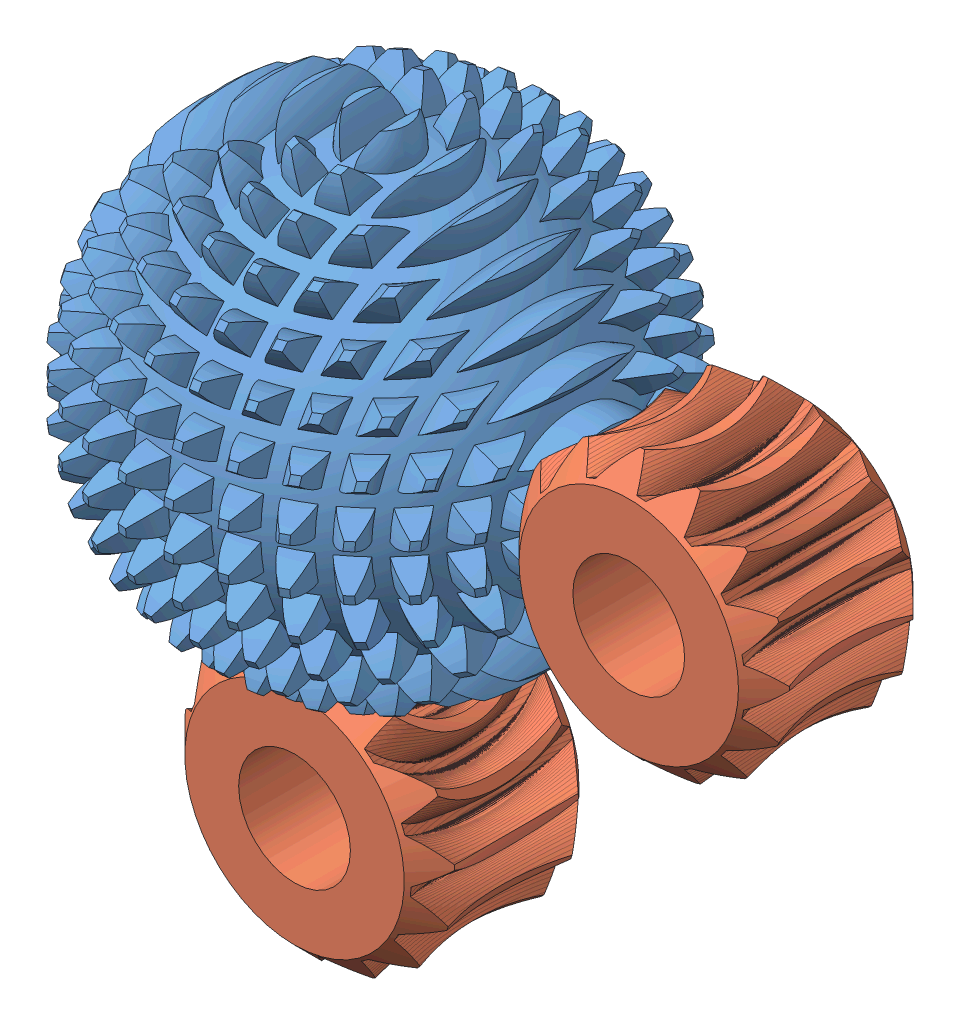
SolidWorks assembly demo, configuration Default. Lengths in mm.
Overall size (51.4 51.4 33.78).
3 component instances, 2 part files, 9 mates.
Components (placement in the parent):
- G_1-1: G_1 [Default] at origin size (33.89 33.89 33.78)
- G_2-1: G_2 [Default] at (0 -23.9999 -0.0806) x (0 1 0) z (0 0 1) size (19.97 21.19 12.5)
- G_2-2: G_2 [Default] at (24 0 0) x (-1 0 0) z (0 0 -1) size (19.97 21.19 12.5)
Mates (geometry in assembly coordinates):
- Coincident1: coincident anti-aligned: plane of G_2-1 through (0 -23.9999 -0.0806) normal (-1 0 0)
- Coincident2: coordinate: point of G_1-1
- Distance1: distance = 24 mm: unknown of G_2-1
- Coincident3: coincident: unknown of G_2-2
- Coincident4: coincident: unknown of G_2-2
- Distance2: distance = 24 mm: unknown of G_2-2
- Parallel1: parallel anti-aligned: plane of G_2-2 through (24 0 0) normal (0 0 -1)
- Parallel2: parallel anti-aligned: unknown of G_2-2
- Parallel4: parallel anti-aligned: plane of G_2-2 through (24 0 0) normal (0 0 -1)
